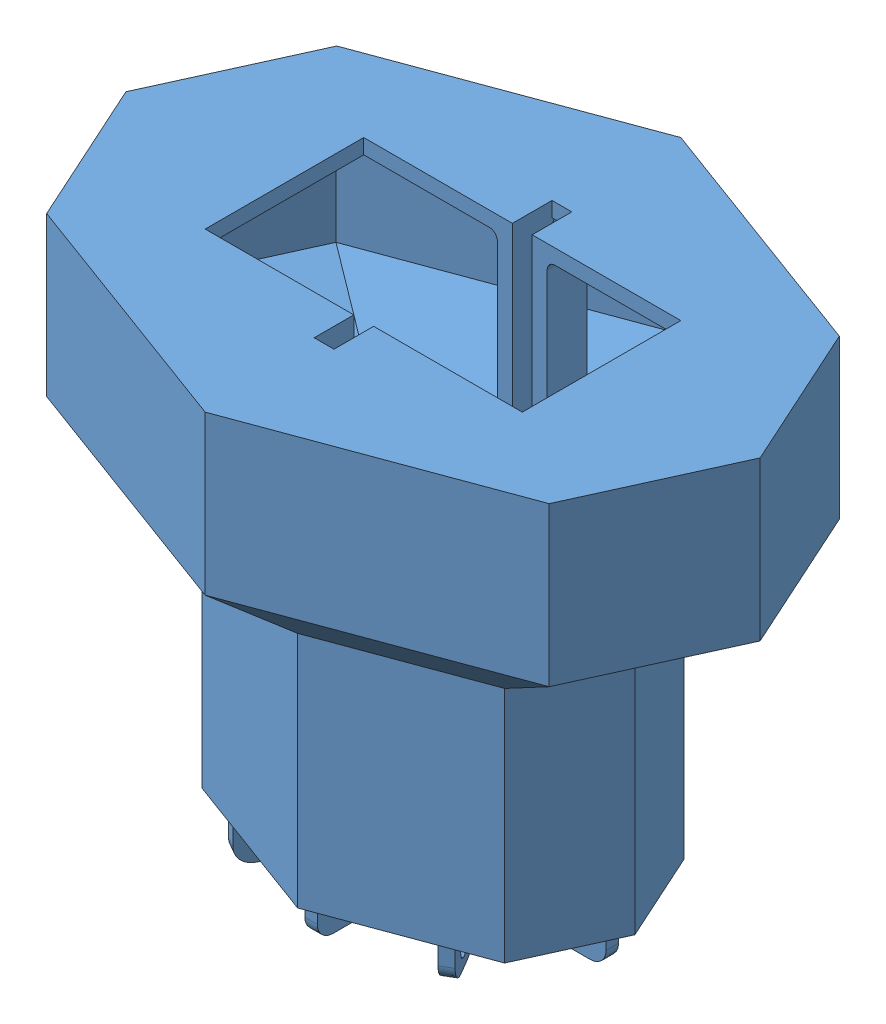
SolidWorks assembly Rev 4 with Pendulum, configuration Default. Lengths in mm.
Overall size (101.6 82.2 76.2).
3 component instances, 3 part files, 5 mates.
Components (placement in the parent):
- Body w Pendulum Model - Rev 4-1: Body w Pendulum Model - Rev 4 [Default] at origin size (101.6 82.2 76.2)
- DowelPin_0.125x1-1: DowelPin_0.125x1 [Default] at (0 -40.5 0) x (0 0 1) z (-1 0 0) size (38.1 3.17 3.17)
- Pendulum_SemiCirc_1to12-1: Pendulum_SemiCirc_1to12 [Default] at (0 -40.5 0) x (-0.999449 0.033205 0) z (0 0 -1) size (44.1 26.99 7.41)
Mates (geometry in assembly coordinates):
- Concentric1: concentric anti-aligned: cylinder of DowelPin_0.125x1-1 through (0 -40.5 19.05) axis (0 0 -1) radius 1.5875; cylinder of Pendulum_SemiCirc_1to12-1 through (0 -40.5 -3.7042) axis (0 0 1) radius 1.5875
- Width1: width aligned: plane of Pendulum_SemiCirc_1to12-1 through (-5.5267 -38.6731 3.7042) normal (0 0 1); plane of Pendulum_SemiCirc_1to12-1 through (-5.5267 -38.6731 -3.7042) normal (0 0 -1); plane of DowelPin_0.125x1-1 through (0 -40.5 19.05) normal (0 0 1); plane of DowelPin_0.125x1-1 through (0 -40.5 -19.05) normal (0 0 -1)
- Concentric2: concentric anti-aligned: cylinder of Body w Pendulum Model - Rev 4-1 through (0 -40.5 -15.875) axis (0 0 1) radius 1.5875; cylinder of DowelPin_0.125x1-1 through (0 -40.5 19.05) axis (0 0 -1) radius 1.5875
- Coincident2: coincident aligned: plane of Body w Pendulum Model - Rev 4-1 through (-3.9875 -40.5 -19.05) normal (0 0 -1); plane of DowelPin_0.125x1-1 through (0 -40.5 -19.05) normal (0 0 -1)
- Coincident4: coordinate: point of Body w Pendulum Model - Rev 4-1; point of assembly
